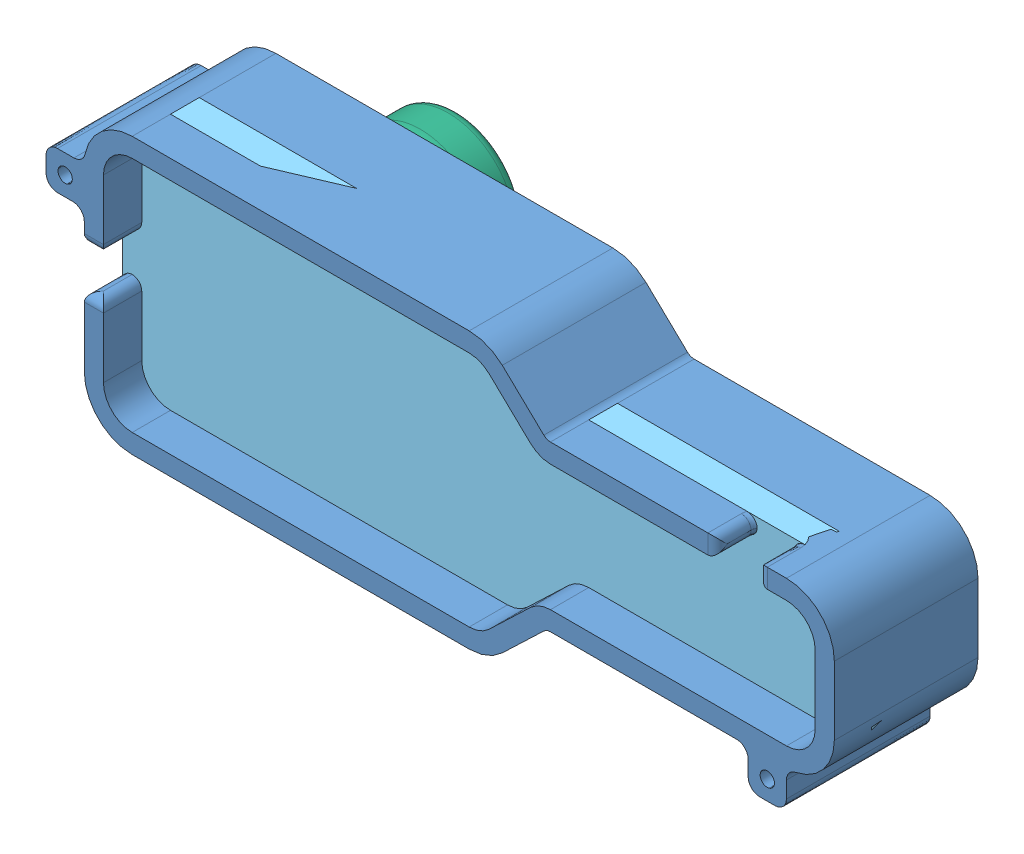
SolidWorks assembly FullModel, configuration Default. Lengths in mm.
Overall size (82.31 28.78 27).
6 component instances, 6 part files, 11 mates.
Components (placement in the parent):
- CaseBottom-1: CaseBottom [Default] at (33.019 -6.2949 -13.147) size (82.31 28.78 15)
- PCB-1: PCB [Default] at (-38.291 -12.1049 -13.147) size (40.02 21.78 3)
- IMU-1: IMU [Default] at (33.019 -6.2949 -10.147) size (34.29 10.16 3)
- Arduino-1: Arduino [Default] at (-3.271 -10.1049 -10.147) size (33.02 17.78 3)
- CaseCover-1: CaseCover [Default] at (33.019 -6.2949 -5.147) size (82.31 28.78 3)
- EarPlug-1: EarPlug [Default] at (-29.791 -1.2149 -16.147) x (0 0 1) z (-1 0 0) size (12 14 14)
Mates (geometry in assembly coordinates):
- Coincident1: coincident anti-aligned: line of CaseBottom-1 through (-38.291 -12.1049 -13.147) axis (0 1 0); line of PCB-1 through (-38.291 9.6751 -13.147) axis (0 -1 0)
- Coincident2: coincident anti-aligned: line of CaseBottom-1 through (-1.271 -12.1049 -13.147) axis (-1 0 0); line of PCB-1 through (-38.291 -12.1049 -13.147) axis (1 0 0)
- Coincident3: coincident anti-aligned: plane of PCB-1 through (-38.291 -12.1049 -10.147) normal (0 0 1); plane of IMU-1 through (33.019 -6.2949 -10.147) normal (0 0 -1)
- Coincident4: coincident: line of CaseBottom-1 through (-1.271 3.8651 -13.147) axis (0 -1 0); plane of IMU-1 through (-1.271 3.8651 -7.147) normal (-1 0 0)
- Coincident5: coincident: line of CaseBottom-1 through (-1.271 3.8651 -13.147) axis (1 0 0); plane of IMU-1 through (-1.271 3.8651 -7.147) normal (0 1 0)
- Coincident6: coincident anti-aligned: plane of PCB-1 through (-38.291 -12.1049 -10.147) normal (0 0 1); plane of Arduino-1 through (-3.271 -10.1049 -10.147) normal (0 0 -1)
- Coincident7: coincident: line of CaseBottom-1 through (-36.291 7.6751 -13.147) axis (1 0 0); plane of Arduino-1 through (-36.291 7.6751 -7.147) normal (0 1 0)
- Coincident8: coincident: line of CaseBottom-1 through (-3.271 7.6751 -13.147) axis (0 -1 0); plane of Arduino-1 through (-3.271 7.6751 -7.147) normal (1 0 0)
- Coincident9: coincident: circle of CaseBottom-1; circle of CaseCover-1
- Coincident11: coincident: plane of CaseBottom-1 through (-36.791 8.1751 -16.147) normal (0 0 -1); plane of EarPlug-1 through (-29.791 2.2851 -16.147) normal (0 0 1)
- Concentric1: concentric anti-aligned: circle of CaseBottom-1; circle of EarPlug-1
